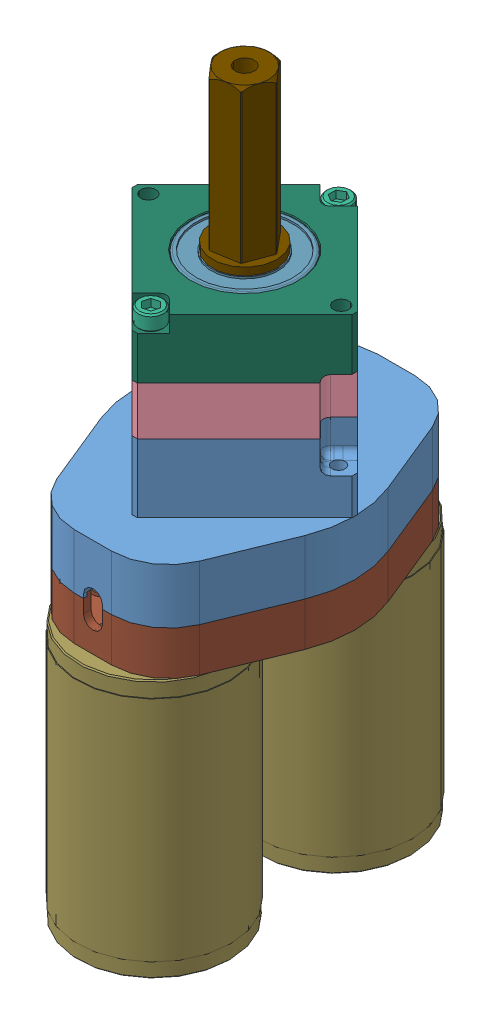
SolidWorks assembly dual_Motor_with_Gearbox, configuration Default. Lengths in mm.
Overall size (87.77 183.81 88.18).
48 component instances, 25 part files, 3 mates.
Components (placement in the parent):
- Dual_Motor_Input_with_BAG_Motor-1: Dual_Motor_Input_with_BAG_Motor [Default] at origin size (58 114.72 88.18)
  - 217-3141-001 Rev1-1: 217-3141-001 Rev1 [Default] x (0 0 1) z (-1 0 0) size (80 14.5 58)
  - 217-3141-007 Rev1_30T 32DP-1: 217-3141-007 Rev1_30T 32DP [Default] at (0 -7.06 0) x (0 -1 0) z (-0.999183 0 0.040426) size (22.38 25.55 25.47)
  - 217-3141-006 Rev1_30T 32DP-1: 217-3141-006 Rev1_30T 32DP [Default] at (0 -9.85 -23.8887) x (-0.095925 0 -0.995389) z (0 -1 0) size (25.47 25.55 10)
  - 217-3141-006 Rev1_30T 32DP-2: 217-3141-006 Rev1_30T 32DP [Default] at (0 -9.85 23.8887) x (-0.001725 0 0.999999) z (0 -1 0) size (25.47 25.55 10)
  - 217-2741-1: 217-2741 [Default] at (0 2.75 0) x (0 -1 0) z (-0.999445 0 -0.033298) size (5 26 26)
  - 217-2741-2: 217-2741 [Default] at (0 -13.25 0) x (0 -1 0) z (-0.537831 0 0.843053) size (5 26 26)
  - PINL-M020-006-S-1: PINL-M020-006-S [Default] at (22.7445 5.75 3.4184) x (0 1 0) z (-0.890225 0 0.455522) size (6 2 2)
  - SSS1032-0188-ZB-1: SSS1032-0188-ZB [Default] at (-0.3489 -11.725 -27.5094) x (-0.758755 -0.647259 0.073121) z (0.095925 0 0.995389) size (4.91 4.91 5.06)
  - SSS1032-0188-ZB-2: SSS1032-0188-ZB [Default] at (-0.0063 -11.725 27.5262) x (0.762269 -0.647259 0.001315) z (0.001725 0 -0.999999) size (4.91 4.91 5.06)
  - NUT-832-NYLOCK-1: NUT-832-NYLOCK [Default] at (19.244 -4.75 -2.0226) x (0.913545 0 0.406737) z (-0.406737 0 0.913545) size (10.2 4.9 8.12)
  - NUT-832-NYLOCK-2: NUT-832-NYLOCK [Default] at (-19.244 -4.75 2.0226) x (0.912648 0 0.408747) z (-0.408747 0 0.912648) size (10.2 4.9 8.12)
  - 91251A346_91251A346-1: 91251A346_91251A346 [Default] at (0 25.975 25.4) x (1 0 0) z (0 1 0) size (7.92 7.92 27.28)
  - 91251A346_91251A346-2: 91251A346_91251A346 [Default] at (0 25.975 -25.4) x (1 0 0) z (0 1 0) size (7.92 7.92 27.28)
  - SSA_SSAM4-0010ZC-1: SSA_SSAM4-0010ZC [Default] at (12.5 -17.25 -23.8887) size (7 14 7)
  - SSA_SSA0832-0750ZC-1: SSA_SSA0832-0750ZC [Default] at (19.244 -19.25 -2.0226) x (-0.091926 0 -0.995766) z (-0.995766 0 0.091926) size (6.73 23.11 6.73)
  - SSA_SSA0832-0750ZC-2: SSA_SSA0832-0750ZC [Default] at (-19.244 -19.25 2.0226) x (-0.18632 0 -0.982489) z (-0.982489 0 0.18632) size (6.73 23.11 6.73)
  - SSA_SSAM4-0010ZC-2: SSA_SSAM4-0010ZC [Default] at (-12.5 -17.25 23.8887) x (0.677756 0 0.735287) z (-0.735287 0 0.677756) size (7 14 7)
  - SSA_SSAM4-0010ZC-3: SSA_SSAM4-0010ZC [Default] at (12.5 -17.25 23.8887) x (0.994338 0 -0.106265) z (0.106265 0 0.994338) size (7 14 7)
  - SSA_SSAM4-0010ZC-4: SSA_SSAM4-0010ZC [Default] at (-12.5 -17.25 -23.8887) x (0.537906 0 -0.843005) z (0.843005 0 0.537906) size (7 14 7)
  - 217-3141-002 Rev2-1: 217-3141-002 Rev2 [Default] at (0 -13 0) x (0 0 1) z (0 1 0) size (80 58 12.5)
  - 217-3351-1: 217-3351 [Default] at (0 -19.25 -23.8887) x (1 0 0) z (0 1 0) size (40.4 40.4 81.5)
  - 217-3351-2: 217-3351 [Default] at (0 -19.25 23.8887) x (1 0 0) z (0 1 0) size (40.4 40.4 81.5)
  - 217-2625-011 Rev1-1: 217-2625-011 Rev1 [Default] at (0 -11.1 -23.8887) x (0.095925 0 0.995389) z (-0.995389 0 0.095925) size (8.01 7.5 7.94)
  - 217-2625-011 Rev1-2: 217-2625-011 Rev1 [Default] at (0 -11 23.8887) x (-0.964857 0 0.262777) z (-0.262777 0 -0.964857) size (8.01 7.5 7.94)
- VersaPlanetary_v1_Single_Stage_10_1-1: VersaPlanetary_v1_Single_Stage_10_1 [Default] at (0 24.75 0) x (-0.707107 0 0.707107) z (0 -1 0) size (62.06 62.06 160.81)
  - 217-2742-001 Rev4-1: 217-2742-001 Rev4 [Default] at (0 0 -19.9002) x (0 0 1) z (-1 0 0) size (7 28 28)
  - 217-2742-001 Rev4-2: 217-2742-001 Rev4 [Default] at (0 0 -28.305) x (0 0 1) z (-0.819238 -0.573454 0) size (7 28 28)
  - 217-2625-002 Rev1-1: 217-2625-002 Rev1 [Default] at (0 0 -6.2) x (-1 0 0) z (0 0 1) size (42 42 17.13)
  - 217-2625-018 Rev1_98541A410-1: 217-2625-018 Rev1_98541A410 [Default] at (0 0 -12.4002) x (0 0 -1) z (0.980859 -0.194721 0) size (1 19.6 17.4)
  - 217-2625-017 Rev1_9714K61-1: 217-2625-017 Rev1_9714K61 [Default] at (0 0 -20.9002) x (-0.695225 0.718792 0) z (-0.718792 -0.695225 0) size (28.51 4.98 30.18)
  - Ouput Shafts^VersaPlanetary_500 Hex-1: Ouput Shafts^VersaPlanetary_500 Hex [Default] at (0 0 -20.5526) x (-0.995515 -0.094608 0) z (0 0 -1) size (17 17 64.12)
    - 217-2625-003 Rev1-1: 217-2625-003 Rev1 [Default] at origin size (17 17 64.12)
  - 217-3564-000 Rev1_BAG-1: 217-3564-000 Rev1_BAG [Default] at (0 0 18) size (42 42 81.5) (hidden)
    - 217-2625-011 Rev1-1: 217-2625-011 Rev1 [Default] at (0 0 -5.25) x (1 0 0) z (0 -1 0) size (8.01 7.5 7.94)
    - 217-2822-003 Rev4-1: 217-2822-003 Rev4 [Default] at (0 0 1.5) size (42 42 4.8)
    - 217-3351-1: 217-3351 [Default] at (0 0 3) x (0 1 0) z (0 0 -1) size (40.4 40.4 81.5) (hidden)
  - Input Housing^VersaPlanetary-1: Input Housing^VersaPlanetary [Default] at (-18.5 13.6657 1) x (0 0 -1) z (-0.885621 0.464408 0) size (20 56.7 56.7)
    - PINL-M020-006-S-1: PINL-M020-006-S [Default] at origin size (6 2 2)
    - 217-2625-001 Rev1-1: 217-2625-001 Rev1 [Default] at (-9.5 3.511 -22.7304) x (0 -0.464408 -0.885621) z (-1 0 0) size (42 42 18)
    - 217-2625-009 Rev1-1: 217-2625-009 Rev1 [Default] at (-6.02 3.511 -22.7304) x (0 0.885621 -0.464408) z (1 0 0) size (18 18 13)
    - SSS1032-0125ZB_94105A824-1: SSS1032-0125ZB_94105A824 [Default] at (-11.495 6.7192 -16.6126) x (-0.636804 0.682837 -0.35807) z (0 0.464408 0.885621) size (4.83 4.84 3.3)
  - 217-2816 Rev1-1: 217-2816 Rev1 [Default] at (0 0 -6.35) x (1 0 0) z (0 0 -1) size (42 42 14.5)
    - 217-2816-001 Rev1-1: 217-2816-001 Rev1 [Default] at origin size (42 42 14.5)
  - 217-2817 Rev1-1: 217-2817 Rev1 [Default] at (0 0 -10.8) x (-0.517538 0.85566 0) z (0 0 -1) size (21.94 21.95 12.7)
    - 217-2724-001 Rev1_Sun_Driver01-1: 217-2724-001 Rev1_Sun_Driver01 [Default] at (0 0 -6.375) x (0.984808 0.173648 0) z (0 0 1) size (18.94 18.95 12.7)
  - SSA_SSA0832-1250ZC-1: SSA_SSA0832-1250ZC [Default] at (-17.5 17.5 -24.061) x (0.699203 0.714923 0) z (-0.714923 0.699203 0) size (6.73 35.81 6.73)
  - SSA_SSA0832-1250ZC-2: SSA_SSA0832-1250ZC [Default] at (17.5 -17.5 -24.061) x (-0.999999 0.001665 0) z (-0.001665 -0.999999 0) size (6.73 35.81 6.73)
Mates (geometry in assembly coordinates):
- Coincident1: coincident: plane of Dual_Motor_Input_with_BAG_Motor-1/217-3141-001 Rev1-1 through (0 6.75 0) normal (0 1 0); plane of VersaPlanetary_v1_Single_Stage_10_1-1/Input Housing^VersaPlanetary-1/217-2625-001 Rev1-1 through (-29.6725 6.75 1.2419) normal (0 -1 0)
- Concentric5: concentric aligned: circle of Dual_Motor_Input_with_BAG_Motor-1/217-3141-007 Rev1_30T 32DP-1; circle of VersaPlanetary_v1_Single_Stage_10_1-1/217-2817 Rev1-1/217-2724-001 Rev1_Sun_Driver01-1
- Angle1: planar angle = 0.785398 rad anti-aligned: plane of assembly; plane of VersaPlanetary_v1_Single_Stage_10_1-1/Input Housing^VersaPlanetary-1/217-2625-001 Rev1-1 through (0 18.25 29.6985) normal (-0.707107 0 0.707107)
